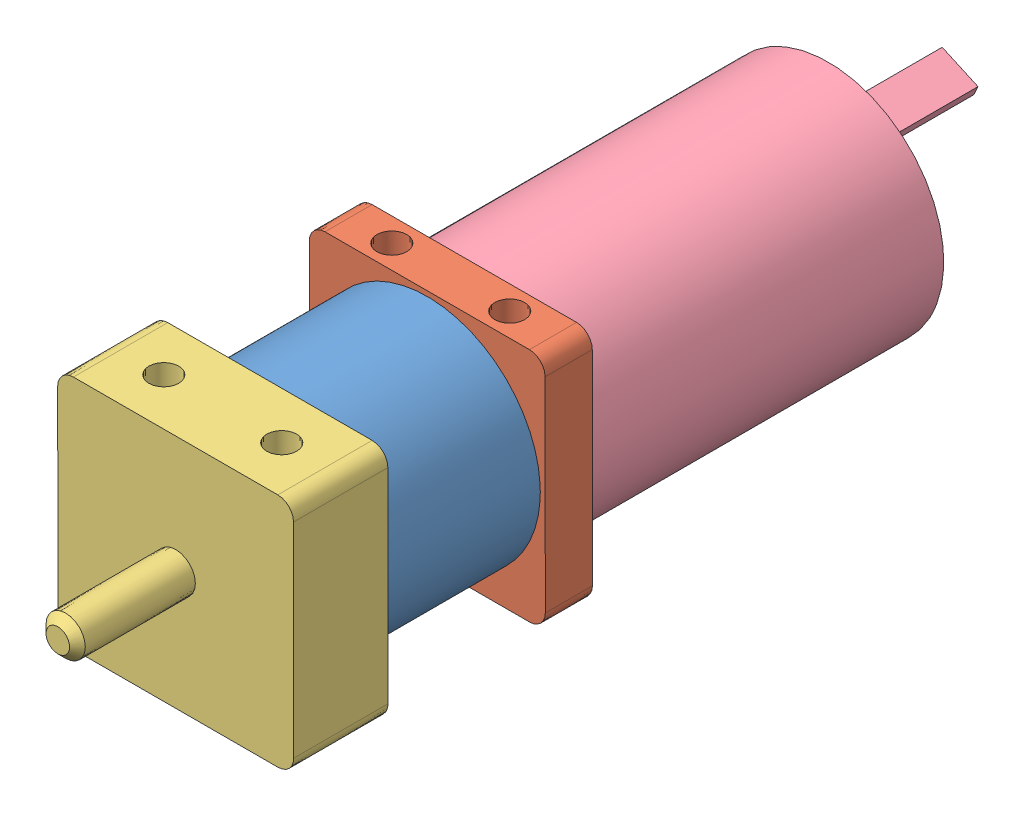
SolidWorks assembly The bamboozler, configuration Default. Lengths in mm.
Overall size (49.42 49.42 139.7).
4 component instances, 4 part files, 8 mates.
Components (placement in the parent):
- Motor Gear thang-1: Motor Gear thang [Default] at (-18.6505 0.7931 -30.0672) size (36.51 36.51 25.4)
- Back thang-1: Back thang [Default] at (-18.6505 0.7931 -37.6872) x (1 0.000908 0) z (0 0 1) size (38.1 38.1 7.62)
- Front thang-2: Front thang [Default] at (-18.6505 0.7931 -4.6672) x (1 0.000908 0) z (0 0 1) size (38.1 38.1 34.29)
- Motor Body-1: Motor Body [Default] at (-18.6505 0.7931 -94.8372) x (0.910927 -0.412569 0) z (0 0 1) size (37.34 37.34 72.39)
Mates (geometry in assembly coordinates):
- Concentric3: concentric: cylinder of Motor Gear thang-1 through (-18.6505 0.7931 -4.6672) axis (0 0 -1) radius 18.2563; cylinder of Back thang-1 through (-18.6505 0.7931 -30.0672) axis (0 0 -1) radius 8.8265
- Coincident3: coincident: plane of Motor Gear thang-1 through (-18.6505 0.7931 -30.0672) normal (0 0 -1); plane of Back thang-1 through (-18.6505 0.7931 -30.0672) normal (0 0 1)
- Concentric4: concentric: circle of Motor Gear thang-1; circle of Front thang-2
- Coincident5: coincident: plane of Motor Gear thang-1 through (-18.6505 0.7931 -4.6672) normal (0 0 1); plane of Front thang-2 through (-18.6505 0.7931 -4.6672) normal (0 0 -1)
- Parallel4: parallel: line of Back thang-1 through (-35.1432 -18.2719 -30.0672) axis (1 0.000908 0); line of Front thang-2 through (-35.1432 -18.2719 -4.6672) axis (1 0.000908 0)
- Concentric6: concentric: circle of Motor Gear thang-1; circle of Back thang-1
- Concentric7: concentric: cylinder of Back thang-1 through (-18.6505 0.7931 -30.0672) axis (0 0 -1) radius 8.8265; cylinder of Motor Body-1 through (-18.6505 0.7931 -62.1495) axis (0 0 -1) radius 18.669
- Coincident7: coincident: plane of Back thang-1 through (-18.6505 0.7931 -37.6872) normal (0 0 -1); plane of Motor Body-1 through (-18.6505 0.7931 -37.6872) normal (0 0 1)
